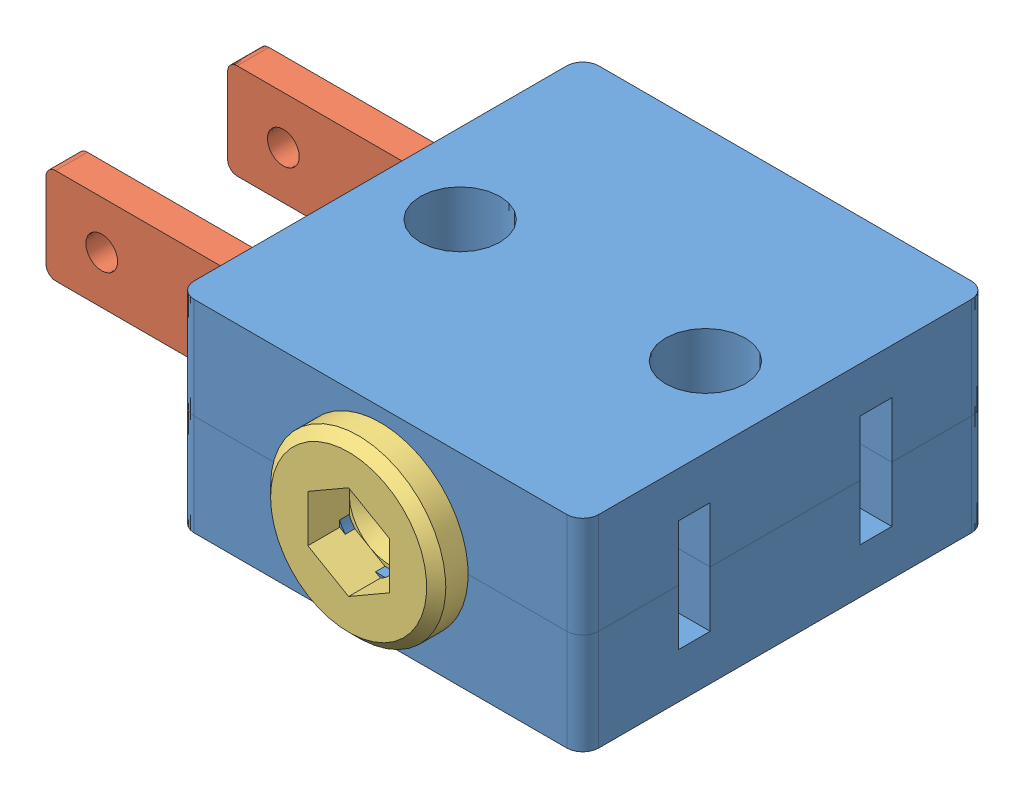
SolidWorks assembly Switch, configuration Default. Lengths in mm.
Overall size (19.85 6.35 13.7).
5 component instances, 3 part files, 11 mates.
Components (placement in the parent):
- BodyHalf-1: BodyHalf [Default] at (-3.5862 16.0327 -0.8872) size (12.7 4.68 12.7)
- BodyHalf-2: BodyHalf [Default] at (-3.5862 22.3827 -13.5872) x (1 0 0) z (0 0 -1) size (12.7 4.68 12.7)
- Terminal-1: Terminal [Default] at (-8.4362 17.7077 -10.5872) x (1 0 0) z (0 -1 0) size (17 1 5)
- Terminal-2: Terminal [Default] at (-8.4362 17.7077 -4.8872) x (1 0 0) z (0 -1 0) size (17 1 5)
- socket head cap screw_am-2: socket head cap screw_am [B18.3.1M - 3 x 0.5 x 6 Hex SHCS -- 6NHX] at (-9.9362 19.2077 0.1128) x (0 0 -1) z (1 0 0) size (9 5.5 5.5)
Mates (geometry in assembly coordinates):
- Concentric1: concentric aligned: cylinder of BodyHalf-1 through (-5.0862 17.7077 -12.0872) axis (0 1 0) radius 0.75; cylinder of BodyHalf-2 through (-5.0862 17.7077 -12.0872) axis (0 1 0) radius 0.75
- Concentric2: concentric aligned: cylinder of BodyHalf-1 through (-14.7862 17.7077 -2.3872) axis (0 1 0) radius 0.75; cylinder of BodyHalf-2 through (-14.7862 17.7077 -2.3872) axis (0 1 0) radius 0.75
- Coincident1: coincident anti-aligned: plane of BodyHalf-1 through (-3.5862 19.2077 -0.8872) normal (0 1 0); plane of BodyHalf-2 through (-3.5862 19.2077 -13.5872) normal (0 -1 0)
- Coincident2: coincident anti-aligned: plane of BodyHalf-1 through (-3.5862 16.7077 -0.8872) normal (0 1 0); plane of Terminal-1 through (-12.9362 16.7077 -9.5872) normal (0 -1 0)
- Coincident3: coincident anti-aligned: plane of BodyHalf-1 through (-6.4362 16.7077 -10.5872) normal (-1 0 0); plane of Terminal-1 through (-6.4362 16.7077 -9.5872) normal (1 0 0)
- Coincident4: coincident anti-aligned: plane of BodyHalf-1 through (-16.2862 17.4577 -9.5872) normal (0 0 -1); plane of Terminal-1 through (-8.4362 17.7077 -9.5872) normal (0 0 1)
- Coincident5: coincident anti-aligned: plane of BodyHalf-1 through (-3.5862 16.7077 -13.5872) normal (0 1 0); plane of Terminal-2 through (-12.9362 16.7077 -3.8872) normal (0 -1 0)
- Coincident6: coincident anti-aligned: plane of BodyHalf-1 through (-6.4362 16.7077 -3.8872) normal (-1 0 0); plane of Terminal-2 through (-6.4362 16.7077 -3.8872) normal (1 0 0)
- Coincident7: coincident anti-aligned: plane of BodyHalf-1 through (-16.2862 17.4577 -3.8872) normal (0 0 -1); plane of Terminal-2 through (-8.4362 17.7077 -3.8872) normal (0 0 1)
- Distance1: distance = 1 mm aligned: plane of BodyHalf-2 through (-3.5862 19.2077 -0.8872) normal (0 0 1); plane of socket head cap screw_am-2 through (-9.9362 19.2077 0.1128) normal (0 0 1)
- Concentric4: concentric aligned: cylinder of BodyHalf-1 through (-9.9362 19.2077 -0.8872) axis (0 0 1) radius 1.397; cylinder of socket head cap screw_am-2 through (-9.9362 19.2077 31.8628) axis (0 0 1) radius 1.5
